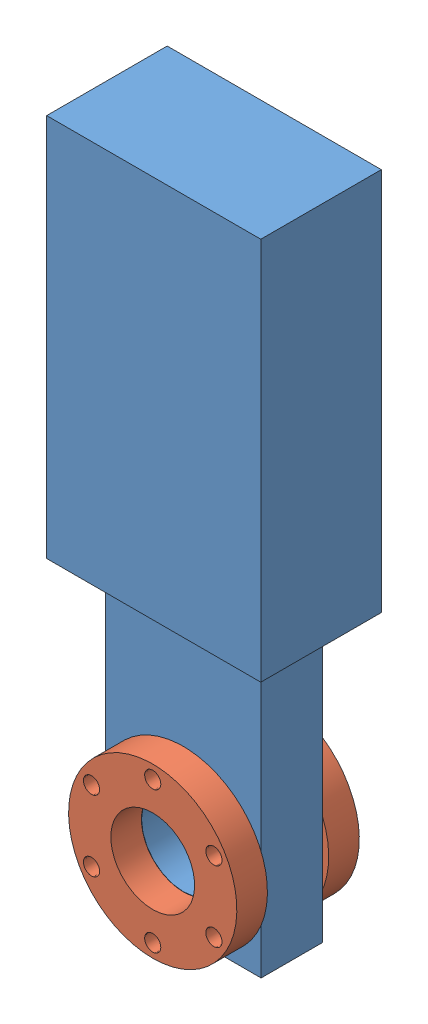
SolidWorks assembly gatevalve, configuration Default. Lengths in mm.
Overall size (88.9 280.54 50.84).
3 component instances, 2 part files, 4 mates.
Components (placement in the parent):
- gatevalve_body-1: gatevalve_body [Default] at (-95.213 2.8522 48.3049) size (88.9 277.88 50.04)
- 2.75in_CF_flange-3: 2.75in_CF_flange [Default] at (-95.213 -24.1988 73.7492) x (1 0 0) z (0 1 0) size (69.85 12.7 69.85)
- 2.75in_CF_flange-4: 2.75in_CF_flange [Default] at (-95.213 -24.1988 35.6049) x (-1 0 0) z (0 -1 0) size (69.85 12.7 69.85)
Mates (geometry in assembly coordinates):
- Concentric2: concentric anti-aligned: circle of gatevalve_body-1; circle of 2.75in_CF_flange-3
- Coincident1: coincident anti-aligned: circle of gatevalve_body-1; circle of 2.75in_CF_flange-4
- Parallel1: parallel anti-aligned: line of 2.75in_CF_flange-3 through (-95.213 -24.1988 73.7492) axis (0 -1 0); line of 2.75in_CF_flange-4 through (-95.213 -24.1988 35.6049) axis (0 1 0)
- Parallel2: parallel aligned: line of gatevalve_body-1 through (-95.213 2.8522 48.3049) axis (0 1 0); line of 2.75in_CF_flange-4 through (-95.213 -24.1988 35.6049) axis (0 1 0)
